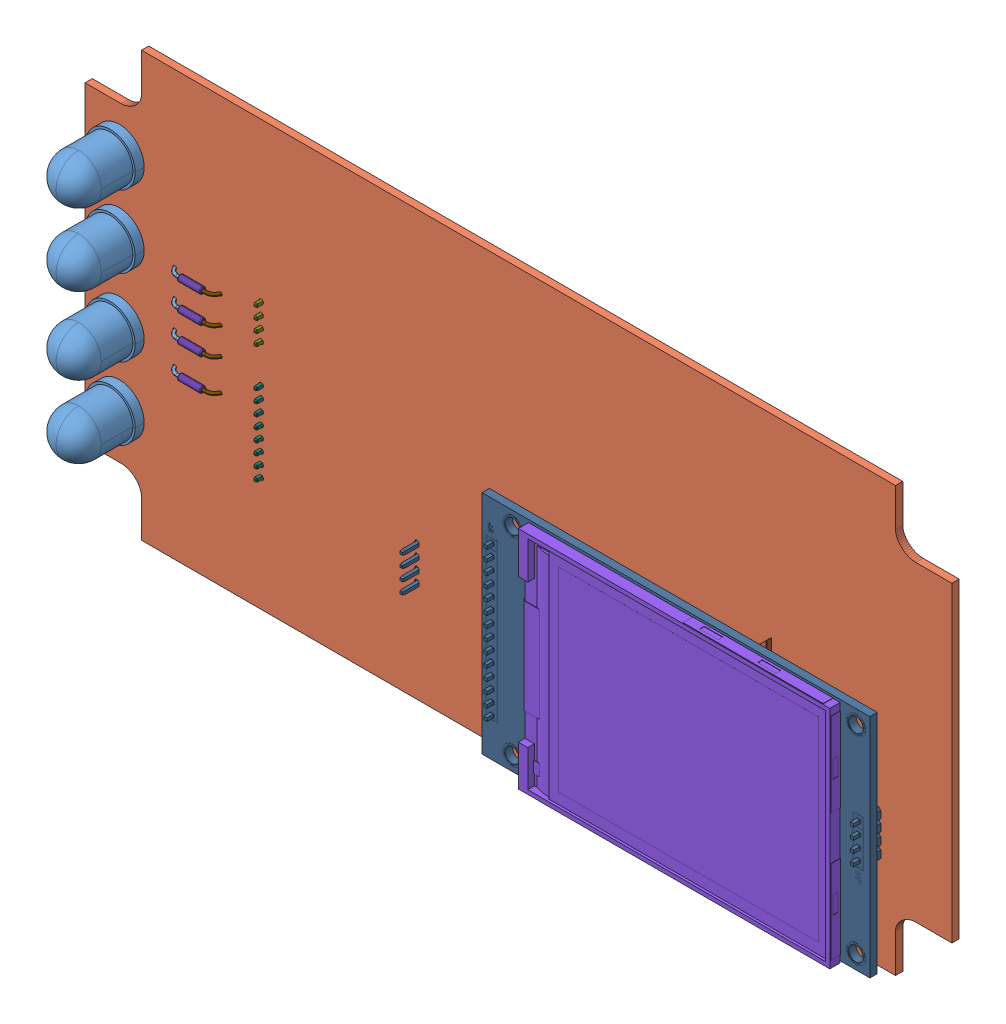
SolidWorks assembly Placa_frontal_V1.0, configuration Valor predeterminado. Lengths in mm.
Overall size (192 94 22.97).
100 component instances, 20 part files, 0 mates.
Components (placement in the parent):
- Placa_frontal_V1.STEP-1: Placa_frontal_V1.STEP [Valor predeterminado] at origin size (192 94 22.97)
  - D1.STEP-1: D1.STEP [Valor predeterminado] at (11 74 0.803) x (-1 0 0) z (0 0 1) size (11 11 19.65)
    - Open CASCADE STEP translator 6.8 5.2.1.STEP-1: Open CASCADE STEP translator 6.8 5.2.1.STEP [Valor predeterminado] at origin size (11 11 19.65)
      - Body_1.STEP-1: Body_1.STEP [Valor predeterminado] at (1.25 0 -3.5) x (1 0 0) z (0 -1 0) size (11 19.65 11)
        - =_[0_1_1_3].STEP-1: =_[0_1_1_3].STEP [Valor predeterminado] at origin size (11 14 11)
        - =_[0_1_1_4].STEP-1: =_[0_1_1_4].STEP [Valor predeterminado] at origin size (0.5 5.65 0.5)
        - =_[0_1_1_5].STEP-1: =_[0_1_1_5].STEP [Valor predeterminado] at origin size (0.5 5.65 0.5)
        - =_[0_1_1_6].STEP-1: =_[0_1_1_6].STEP [Valor predeterminado] at origin size (0.6 0.65 0.5)
        - =_[0_1_1_7].STEP-1: =_[0_1_1_7].STEP [Valor predeterminado] at origin size (0.6 0.65 0.5)
  - D2.STEP-1: D2.STEP [Valor predeterminado] at (11 58 0.803) x (-1 0 0) z (0 0 1) size (11 11 19.65)
    - Open CASCADE STEP translator 6.8 5.3.1.STEP-1: Open CASCADE STEP translator 6.8 5.3.1.STEP [Valor predeterminado] at origin size (11 11 19.65)
      - Body_1.STEP-1: Body_1.STEP [Valor predeterminado] at (1.25 0 -3.5) x (1 0 0) z (0 -1 0) size (11 19.65 11)
        - =_[0_1_1_3].STEP-1: =_[0_1_1_3].STEP [Valor predeterminado] at origin size (11 14 11)
        - =_[0_1_1_4].STEP-1: =_[0_1_1_4].STEP [Valor predeterminado] at origin size (0.5 5.65 0.5)
        - =_[0_1_1_5].STEP-1: =_[0_1_1_5].STEP [Valor predeterminado] at origin size (0.5 5.65 0.5)
        - =_[0_1_1_6].STEP-1: =_[0_1_1_6].STEP [Valor predeterminado] at origin size (0.6 0.65 0.5)
        - =_[0_1_1_7].STEP-1: =_[0_1_1_7].STEP [Valor predeterminado] at origin size (0.6 0.65 0.5)
  - D3.STEP-1: D3.STEP [Valor predeterminado] at (11 41 0.803) x (-1 0 0) z (0 0 1) size (11 11 19.65)
    - Open CASCADE STEP translator 6.8 5.4.1.STEP-1: Open CASCADE STEP translator 6.8 5.4.1.STEP [Valor predeterminado] at origin size (11 11 19.65)
      - Body_1.STEP-1: Body_1.STEP [Valor predeterminado] at (1.25 0 -3.5) x (1 0 0) z (0 -1 0) size (11 19.65 11)
        - =_[0_1_1_3].STEP-1: =_[0_1_1_3].STEP [Valor predeterminado] at origin size (11 14 11)
        - =_[0_1_1_4].STEP-1: =_[0_1_1_4].STEP [Valor predeterminado] at origin size (0.5 5.65 0.5)
        - =_[0_1_1_5].STEP-1: =_[0_1_1_5].STEP [Valor predeterminado] at origin size (0.5 5.65 0.5)
        - =_[0_1_1_6].STEP-1: =_[0_1_1_6].STEP [Valor predeterminado] at origin size (0.6 0.65 0.5)
        - =_[0_1_1_7].STEP-1: =_[0_1_1_7].STEP [Valor predeterminado] at origin size (0.6 0.65 0.5)
  - D4.STEP-1: D4.STEP [Valor predeterminado] at (11 25 0.803) x (-1 0 0) z (0 0 1) size (11 11 19.65)
    - Open CASCADE STEP translator 6.8 5.5.1.STEP-1: Open CASCADE STEP translator 6.8 5.5.1.STEP [Valor predeterminado] at origin size (11 11 19.65)
      - Body_1.STEP-1: Body_1.STEP [Valor predeterminado] at (1.25 0 -3.5) x (1 0 0) z (0 -1 0) size (11 19.65 11)
        - =_[0_1_1_3].STEP-1: =_[0_1_1_3].STEP [Valor predeterminado] at origin size (11 14 11)
        - =_[0_1_1_4].STEP-1: =_[0_1_1_4].STEP [Valor predeterminado] at origin size (0.5 5.65 0.5)
        - =_[0_1_1_5].STEP-1: =_[0_1_1_5].STEP [Valor predeterminado] at origin size (0.5 5.65 0.5)
        - =_[0_1_1_6].STEP-1: =_[0_1_1_6].STEP [Valor predeterminado] at origin size (0.6 0.65 0.5)
        - =_[0_1_1_7].STEP-1: =_[0_1_1_7].STEP [Valor predeterminado] at origin size (0.6 0.65 0.5)
  - A1.STEP-1: A1.STEP [Valor predeterminado] at (96.2 24 0.803) size (85.9 50.19 11.99)
    - Open CASCADE STEP translator 6.8 5.6.1.STEP-1: Open CASCADE STEP translator 6.8 5.6.1.STEP [Valor predeterminado] at origin size (85.9 50.19 11.99)
      - Body_1-1.STEP-1: Body_1-1.STEP [Valor predeterminado] at (40.8 3.9 2.5) x (0 1 0) z (0 0 1) size (50.19 85.9 11.99)
        - 2.8in_TFT(Without_Glass)-_Tucked_Cable.STEP-1: 2.8in_TFT(Without_Glass)-_Tucked_Cable.STEP [Valor predeterminado] at (-0.0571 -2.2987 1.6256) x (-1 0 0) z (0 0 1) size (50.11 69.48 2.83)
          - SOLID.STEP-1: SOLID.STEP [Valor predeterminado] at origin size (0.29 0.77 0.02)
          - SOLID-0.STEP-1: SOLID-0.STEP [Valor predeterminado] at origin size (0.29 0.75 0.02)
          - SOLID-1.STEP-1: SOLID-1.STEP [Valor predeterminado] at origin size (50.11 69.48 2.72)
          - SOLID-2.STEP-1: SOLID-2.STEP [Valor predeterminado] at origin size (0.53 0.77 0.23)
        - 2.8_LCD_TFT_Module_-_Without_Glass.STEP-1: 2.8_LCD_TFT_Module_-_Without_Glass.STEP [Valor predeterminado] at origin size (50.14 85.9 10.67)
        - 5035000993.STEP-1: 5035000993.STEP [Valor predeterminado] at (3.5564 -3.3047 -2.85) x (0 1 0) z (0 0 -1) size (28.6 21.52 2.95)
        - 0603_Resistor.STEP-1: 0603_Resistor.STEP [Valor predeterminado] at (-2.2311 -3.165 0.0025) x (-1 0 0) z (0 0 -1) size (1.6 0.85 0.56)
        - 0603_Capacitor.STEP-1: 0603_Capacitor.STEP [Valor predeterminado] at (-14.5217 25.6289 0.0025) x (1 0 0) z (0 0 -1) size (1.6 0.84 0.84)
        - 0603_Capacitor.STEP-2: 0603_Capacitor.STEP [Valor predeterminado] at (-2.484 19.738 0.0025) x (-1 0 0) z (0 0 -1) size (1.6 0.84 0.84)
        - 0603_Resistor.STEP-2: 0603_Resistor.STEP [Valor predeterminado] at (-3.8795 -4.7617 0.0025) x (1 0 0) z (0 0 -1) size (1.6 0.85 0.56)
        - 0603_Resistor.STEP-3: 0603_Resistor.STEP [Valor predeterminado] at (-2.3355 -0.9936 0.0025) x (-1 0 0) z (0 0 -1) size (1.6 0.85 0.56)
        - 0603_Resistor.STEP-4: 0603_Resistor.STEP [Valor predeterminado] at (-12.9341 26.6747 0.0025) x (-1 0 0) z (0 0 -1) size (1.6 0.85 0.56)
        - 0603_Resistor.STEP-5: 0603_Resistor.STEP [Valor predeterminado] at (4.5338 19.5922 0.0025) x (-1 0 0) z (0 0 -1) size (1.6 0.85 0.56)
        - 0603_Resistor.STEP-6: 0603_Resistor.STEP [Valor predeterminado] at (4.3803 26.5372 0.0025) x (-1 0 0) z (0 0 -1) size (1.6 0.85 0.56)
        - SOT23-3.STEP-1: SOT23-3.STEP [Valor predeterminado] at (3.6167 23.9432 0.105) x (0.003406 0.999994 0) z (0 0 -1) size (2.87 3.01 1.21)
        - SOT23-3.STEP-2: SOT23-3.STEP [Valor predeterminado] at (-3.3735 23.944 0.105) x (0.999985 -0.005499 0) z (0 0 -1) size (2.87 3.01 1.21)
  - DISPLAY.STEP-1: DISPLAY.STEP [Valor predeterminado] at (41 45 -0.803) x (0 -1 0) z (0 0 -1) size (22.17 5.84 10.21)
    - Open CASCADE STEP translator 6.8 5.7.1.STEP-1: Open CASCADE STEP translator 6.8 5.7.1.STEP [Valor predeterminado] at origin size (22.17 5.84 10.21)
      - Body_1-3.STEP-1: Body_1-3.STEP [Valor predeterminado] at (8.8 0 0) size (22.17 5.84 10.21)
  - LEDS.STEP-1: LEDS.STEP [Valor predeterminado] at (41 61 -0.803) x (0 -1 0) z (0 0 -1) size (12.17 5.84 10.21)
    - Open CASCADE STEP translator 6.8 5.8.1.STEP-1: Open CASCADE STEP translator 6.8 5.8.1.STEP [Valor predeterminado] at origin size (12.17 5.84 10.21)
      - Body_1-4.STEP-1: Body_1-4.STEP [Valor predeterminado] at (3.8 0 0) size (12.17 5.84 10.21)
  - R1.STEP-1: R1.STEP [Valor predeterminado] at (32 58 0.803) x (-1 0 0) z (0 0 1) size (10.82 1.37 5.33)
    - Open CASCADE STEP translator 6.8 5.9.1.STEP-1: Open CASCADE STEP translator 6.8 5.9.1.STEP [Valor predeterminado] at origin size (10.82 1.37 5.33)
      - Body_1-5.STEP-1: Body_1-5.STEP [Valor predeterminado] at origin size (5.08 1.37 1.37)
      - Pin_1.STEP-1: Pin_1.STEP [Valor predeterminado] at origin size (3.2 0.66 4.98)
      - Pin_2.STEP-1: Pin_2.STEP [Valor predeterminado] at (20.32 0 0) x (-1 0 0) z (0 0 1) size (3.2 0.66 4.98)
  - R2.STEP-1: R2.STEP [Valor predeterminado] at (32 52 0.803) x (-1 0 0) z (0 0 1) size (10.82 1.37 5.33)
    - Open CASCADE STEP translator 6.8 5.9.1.STEP-1: Open CASCADE STEP translator 6.8 5.9.1.STEP [Valor predeterminado] at origin size (10.82 1.37 5.33)
      - Body_1-5.STEP-1: Body_1-5.STEP [Valor predeterminado] at origin size (5.08 1.37 1.37)
      - Pin_1.STEP-1: Pin_1.STEP [Valor predeterminado] at origin size (3.2 0.66 4.98)
      - Pin_2.STEP-1: Pin_2.STEP [Valor predeterminado] at (20.32 0 0) x (-1 0 0) z (0 0 1) size (3.2 0.66 4.98)
  - R3.STEP-1: R3.STEP [Valor predeterminado] at (32 46 0.803) x (-1 0 0) z (0 0 1) size (10.82 1.37 5.33)
    - Open CASCADE STEP translator 6.8 5.9.1.STEP-1: Open CASCADE STEP translator 6.8 5.9.1.STEP [Valor predeterminado] at origin size (10.82 1.37 5.33)
      - Body_1-5.STEP-1: Body_1-5.STEP [Valor predeterminado] at origin size (5.08 1.37 1.37)
      - Pin_1.STEP-1: Pin_1.STEP [Valor predeterminado] at origin size (3.2 0.66 4.98)
      - Pin_2.STEP-1: Pin_2.STEP [Valor predeterminado] at (20.32 0 0) x (-1 0 0) z (0 0 1) size (3.2 0.66 4.98)
  - R4.STEP-1: R4.STEP [Valor predeterminado] at (32 39 0.803) x (-1 0 0) z (0 0 1) size (10.82 1.37 5.33)
    - Open CASCADE STEP translator 6.8 5.9.1.STEP-1: Open CASCADE STEP translator 6.8 5.9.1.STEP [Valor predeterminado] at origin size (10.82 1.37 5.33)
      - Body_1-5.STEP-1: Body_1-5.STEP [Valor predeterminado] at origin size (5.08 1.37 1.37)
      - Pin_1.STEP-1: Pin_1.STEP [Valor predeterminado] at origin size (3.2 0.66 4.98)
      - Pin_2.STEP-1: Pin_2.STEP [Valor predeterminado] at (20.32 0 0) x (-1 0 0) z (0 0 1) size (3.2 0.66 4.98)
  - A2.STEP-1: A2.STEP [Valor predeterminado] at (156.8 24.1 -0.803) x (-1 0 0) z (0 0 -1) size (85.9 50.19 11.99)
    - Open CASCADE STEP translator 6.8 5.13.1.STEP-1: Open CASCADE STEP translator 6.8 5.13.1.STEP [Valor predeterminado] at origin size (85.9 50.19 11.99)
      - Body_1-1.STEP-1: Body_1-1.STEP [Valor predeterminado] at (40.8 3.9 2.5) x (0 1 0) z (0 0 1) size (50.19 85.9 11.99)
        - 2.8in_TFT(Without_Glass)-_Tucked_Cable.STEP-1: 2.8in_TFT(Without_Glass)-_Tucked_Cable.STEP [Valor predeterminado] at (-0.0571 -2.2987 1.6256) x (-1 0 0) z (0 0 1) size (50.11 69.48 2.83)
          - SOLID.STEP-1: SOLID.STEP [Valor predeterminado] at origin size (0.29 0.77 0.02)
          - SOLID-0.STEP-1: SOLID-0.STEP [Valor predeterminado] at origin size (0.29 0.75 0.02)
          - SOLID-1.STEP-1: SOLID-1.STEP [Valor predeterminado] at origin size (50.11 69.48 2.72)
          - SOLID-2.STEP-1: SOLID-2.STEP [Valor predeterminado] at origin size (0.53 0.77 0.23)
        - 2.8_LCD_TFT_Module_-_Without_Glass.STEP-1: 2.8_LCD_TFT_Module_-_Without_Glass.STEP [Valor predeterminado] at origin size (50.14 85.9 10.67)
        - 5035000993.STEP-1: 5035000993.STEP [Valor predeterminado] at (3.5564 -3.3047 -2.85) x (0 1 0) z (0 0 -1) size (28.6 21.52 2.95)
        - 0603_Resistor.STEP-1: 0603_Resistor.STEP [Valor predeterminado] at (-2.2311 -3.165 0.0025) x (-1 0 0) z (0 0 -1) size (1.6 0.85 0.56)
        - 0603_Capacitor.STEP-1: 0603_Capacitor.STEP [Valor predeterminado] at (-14.5217 25.6289 0.0025) x (1 0 0) z (0 0 -1) size (1.6 0.84 0.84)
        - 0603_Capacitor.STEP-2: 0603_Capacitor.STEP [Valor predeterminado] at (-2.484 19.738 0.0025) x (-1 0 0) z (0 0 -1) size (1.6 0.84 0.84)
        - 0603_Resistor.STEP-2: 0603_Resistor.STEP [Valor predeterminado] at (-3.8795 -4.7617 0.0025) x (1 0 0) z (0 0 -1) size (1.6 0.85 0.56)
        - 0603_Resistor.STEP-3: 0603_Resistor.STEP [Valor predeterminado] at (-2.3355 -0.9936 0.0025) x (-1 0 0) z (0 0 -1) size (1.6 0.85 0.56)
        - 0603_Resistor.STEP-4: 0603_Resistor.STEP [Valor predeterminado] at (-12.9341 26.6747 0.0025) x (-1 0 0) z (0 0 -1) size (1.6 0.85 0.56)
        - 0603_Resistor.STEP-5: 0603_Resistor.STEP [Valor predeterminado] at (4.5338 19.5922 0.0025) x (-1 0 0) z (0 0 -1) size (1.6 0.85 0.56)
        - 0603_Resistor.STEP-6: 0603_Resistor.STEP [Valor predeterminado] at (4.3803 26.5372 0.0025) x (-1 0 0) z (0 0 -1) size (1.6 0.85 0.56)
        - SOT23-3.STEP-1: SOT23-3.STEP [Valor predeterminado] at (3.6167 23.9432 0.105) x (0.003406 0.999994 0) z (0 0 -1) size (2.87 3.01 1.21)
        - SOT23-3.STEP-2: SOT23-3.STEP [Valor predeterminado] at (-3.3735 23.944 0.105) x (0.999985 -0.005499 0) z (0 0 -1) size (2.87 3.01 1.21)
  - Layer_1.STEP-1: Layer_1.STEP [Valor predeterminado] at origin size (192 94 1.61)
